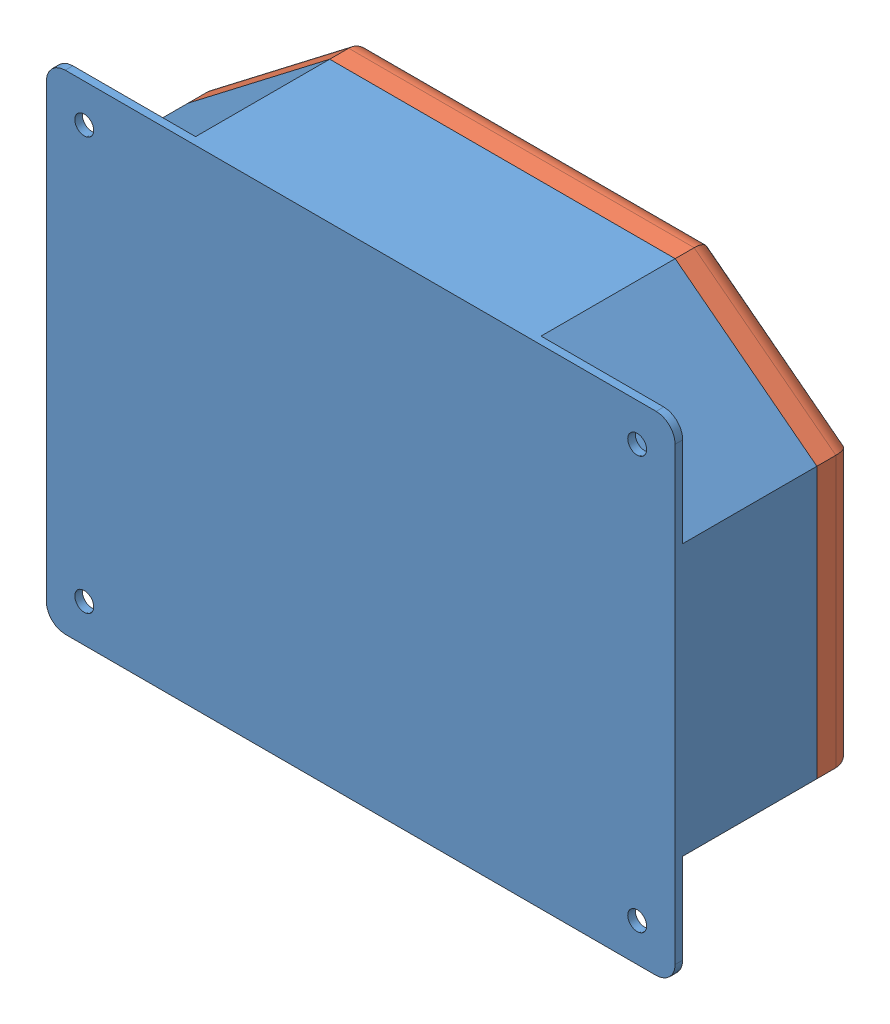
SolidWorks assembly Assem1, configuration Default. Lengths in mm.
Overall size (99.4 77.22 28.4).
2 component instances, 2 part files, 3 mates.
Components (placement in the parent):
- Curie Box-1: Curie Box [Default] at (-14.6822 53.9042 -8.225) size (99.4 77.22 24.4)
- Curie Box Cap-1: Curie Box Cap [Default] at (-14.6822 53.9042 1.775) size (99.4 77.22 6)
Mates (geometry in assembly coordinates):
- Coincident1: coincident anti-aligned: plane of Curie Box-1 through (-14.6822 53.9042 -28.225) normal (0 0 -1); plane of Curie Box Cap-1 through (-14.6822 53.9042 -28.225) normal (0 0 1)
- Coincident2: coincident aligned: line of Curie Box-1 through (68.9023 33.0068 -28.225) axis (0 -1 0); line of Curie Box Cap-1 through (68.9023 33.0068 -28.225) axis (0 -1 0)
- Coincident3: coincident aligned: line of Curie Box-1 through (-8.0977 50.2239 -28.225) axis (1 0 0); line of Curie Box Cap-1 through (-8.0977 50.2239 -28.225) axis (1 0 0)
